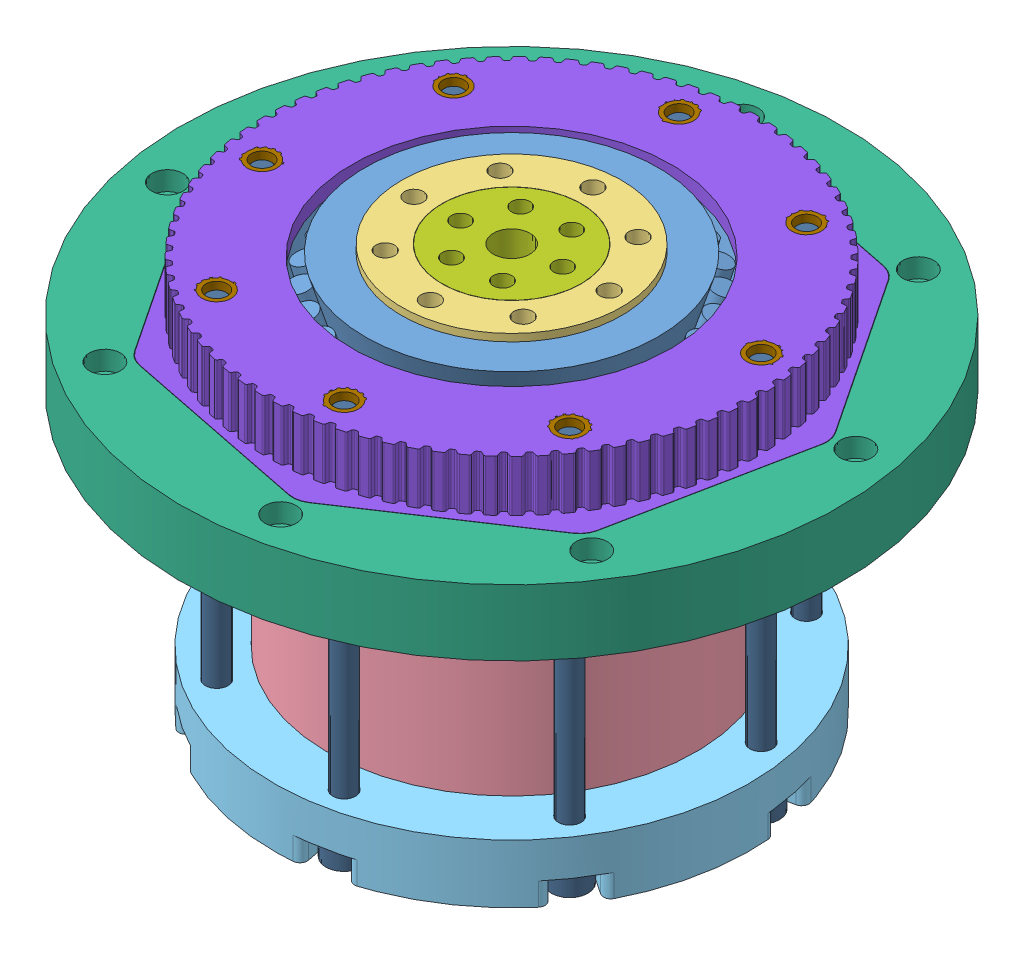
SolidWorks assembly Assemblage1, configuration Défaut. Lengths in mm.
Overall size (211.39 121 211.39).
25 component instances, 11 part files, 51 mates.
Components (placement in the parent):
- Roulement Conique 95x60x23-1: Roulement Conique 95x60x23 [Défaut] at (-13.8203 2.5153 0) x (-0.853201 0 0.521582) z (-0.521582 0 -0.853201) size (95 23 95)
- Roulement 68x40x15-1: Roulement 68x40x15 [Défaut] at (-13.8203 -87.4847 0) size (68 15 68)
- BaguePivot1-1: BaguePivot1 [Défaut] at (-13.8203 27.5153 0) x (-0.768543 0 -0.639798) z (-0.639798 0 0.768543) size (60 20 60)
- Tube d100x100-1: Tube d100x100 [Défaut] at (-13.8203 -73.4847 0) size (100.4 70 100.4)
- BagueInf1-1: BagueInf1 [Défaut] at (-13.8203 -87.4847 0) x (0.981157 0 -0.19321) z (0.19321 0 0.981157) size (130 20 130)
- BagueSup1-1: BagueSup1 [Défaut] at (-13.8203 -9.4847 0) x (0.981157 0 -0.19321) z (0.19321 0 0.981157) size (180 20 180)
- AxePivot1-1: AxePivot1 [Défaut] at (-13.8203 -82.4847 0) x (0.920291 0 0.391234) z (-0.391234 0 0.920291) size (41 110 41)
- BagueSup2-1: BagueSup2 [Défaut] at (-13.8203 8.5153 0) x (0.981157 0 -0.19321) z (0.19321 0 0.981157) size (148.13 16 148.13)
- M6_insert-2: M6_insert [Défaut] at (-2.6142 11.8153 56.9071) size (8.69 12.7 8.66)
- M6_insert-3: M6_insert [Défaut] at (-46.1358 11.8153 48.1634) size (8.69 12.7 8.66)
- M6_insert-4: M6_insert [Défaut] at (-70.7275 11.8153 11.2062) size (8.69 12.7 8.66)
- M6_insert-5: M6_insert [Défaut] at (-61.9837 11.8153 -32.3155) size (8.69 12.7 8.66)
- M6_insert-6: M6_insert [Défaut] at (34.343 11.8153 32.3155) size (8.69 12.7 8.66)
- M6_insert-7: M6_insert [Défaut] at (43.0868 11.8153 -11.2062) size (8.69 12.7 8.66)
- M6_insert-8: M6_insert [Défaut] at (18.4951 11.8153 -48.1634) size (8.69 12.7 8.66)
- M6_insert-9: M6_insert [Défaut] at (-25.0265 11.8153 -56.9071) size (8.69 12.7 8.66)
- M6x100_vis-2: M6x100_vis [Défaut] at (18.4951 -83.2847 -48.1634) x (1 0 0) z (0 1 0) size (10 10 106)
- M6x100_vis-3: M6x100_vis [Défaut] at (-25.0265 -83.2847 -56.9071) x (1 0 0) z (0 1 0) size (10 10 106)
- M6x100_vis-4: M6x100_vis [Défaut] at (-61.9837 -83.2847 -32.3155) x (1 0 0) z (0 1 0) size (10 10 106)
- M6x100_vis-5: M6x100_vis [Défaut] at (-70.7275 -83.2847 11.2062) x (1 0 0) z (0 1 0) size (10 10 106)
- M6x100_vis-6: M6x100_vis [Défaut] at (-46.1358 -83.2847 48.1634) x (1 0 0) z (0 1 0) size (10 10 106)
- M6x100_vis-7: M6x100_vis [Défaut] at (-2.6142 -83.2847 56.9071) x (1 0 0) z (0 1 0) size (10 10 106)
- M6x100_vis-8: M6x100_vis [Défaut] at (34.343 -83.2847 32.3155) x (1 0 0) z (0 1 0) size (10 10 106)
- M6x100_vis-9: M6x100_vis [Défaut] at (43.0868 -83.2847 -11.2062) x (1 0 0) z (0 1 0) size (10 10 106)
- BouchonInf1-1: BouchonInf1 [Défaut] at (-13.8203 -83.4847 0) x (-0.920291 0 -0.391234) z (-0.391234 0 0.920291) size (50 10 50)
Mates (geometry in assembly coordinates):
- Coaxiale1: concentric anti-aligned: cylinder of Roulement Conique 95x60x23-1 through (-13.8203 2.5153 0) axis (0 -1 0) radius 30; cylinder of BaguePivot1-1 through (-13.8203 7.5153 0) axis (0 1 0) radius 30
- Coaxiale2: concentric aligned: cylinder of Roulement 68x40x15-1 through (-13.8203 -72.4847 0) axis (0 -1 0) radius 34; cylinder of BagueInf1-1 through (-13.8203 -87.4847 0) axis (0 -1 0) radius 34.05
- Coïncidente1: coincident anti-aligned: plane of Roulement 68x40x15-1 through (-13.8203 -72.4847 0) normal (0 1 0); plane of BagueInf1-1 through (-47.2287 -72.4847 6.5788) normal (0 -1 0)
- Coaxiale3: concentric aligned: cylinder of Tube d100x100-1 through (-13.8203 -3.4847 0) axis (0 -1 0) radius 50.2; cylinder of BagueInf1-1 through (-13.8203 -87.4847 0) axis (0 -1 0) radius 50.3
- Coïncidente2: coincident anti-aligned: plane of Tube d100x100-1 through (-13.8203 -73.4847 0) normal (0 -1 0); plane of BagueInf1-1 through (-60.0328 -73.4847 9.1002) normal (0 1 0)
- Coaxiale4: concentric aligned: cylinder of Tube d100x100-1 through (-13.8203 -3.4847 0) axis (0 -1 0) radius 50.2; cylinder of BagueSup1-1 through (-13.8203 -9.4847 0) axis (0 -1 0) radius 50.3
- Coïncidente3: coincident anti-aligned: plane of Tube d100x100-1 through (-13.8203 -3.4847 0) normal (0 1 0); plane of BagueSup1-1 through (-63.1725 -3.4847 9.7185) normal (0 -1 0)
- Coaxiale5: concentric aligned: cylinder of Roulement Conique 95x60x23-1 through (-13.8203 2.5153 0) axis (0 -1 0) radius 47.5; cylinder of BagueSup1-1 through (-13.8203 -9.4847 0) axis (0 -1 0) radius 47.55
- Coïncidente4: coincident anti-aligned: plane of Roulement Conique 95x60x23-1 through (26.7067 2.5153 -24.7752) normal (0 -1 0); plane of BagueSup1-1 through (-53.6063 2.5153 7.8347) normal (0 1 0)
- Coaxiale6: concentric aligned: cylinder of BagueInf1-1 through (-25.0265 -67.4847 -56.9071) axis (0 -1 0) radius 3.1; cylinder of BagueSup1-1 through (-25.0265 10.5153 -56.9071) axis (0 -1 0) radius 3.1
- Coaxiale7: concentric aligned: cylinder of BaguePivot1-1 through (-13.8203 7.5153 0) axis (0 1 0) radius 19; cylinder of AxePivot1-1 through (-13.8203 5.5153 0) axis (0 1 0) radius 18.95
- Coaxiale8: concentric aligned: cylinder of Roulement Conique 95x60x23-1 through (-13.8203 2.5153 0) axis (0 -1 0) radius 47.5; cylinder of BagueSup2-1 through (-13.8203 24.5153 0) axis (0 -1 0) radius 47.55
- Coaxiale9: concentric anti-aligned: cylinder of BagueSup1-1 through (43.0868 10.5153 -11.2062) axis (0 -1 0) radius 3.1; cylinder of BagueSup2-1 through (43.0868 8.5153 -11.2062) axis (0 1 0) radius 3.1
- Coïncidente7: coincident anti-aligned: plane of BagueSup1-1 through (-13.8203 8.5153 0) normal (0 1 0); plane of BagueSup2-1 through (-13.8203 8.5153 0) normal (0 -1 0)
- Coaxiale101: concentric anti-aligned: cylinder of BagueSup2-1 through (-2.6142 11.7153 56.9071) axis (0 1 0) radius 4; cylinder of M6_insert-2 through (-2.6142 24.5153 56.9071) axis (0 -1 0) radius 2.9
- Coaxiale111: concentric anti-aligned: cylinder of BagueSup2-1 through (-46.1358 11.7153 48.1634) axis (0 1 0) radius 4; cylinder of M6_insert-3 through (-46.1358 24.5153 48.1634) axis (0 -1 0) radius 2.9
- Coaxiale121: concentric anti-aligned: cylinder of BagueSup2-1 through (-70.7275 11.7153 11.2062) axis (0 1 0) radius 4; cylinder of M6_insert-4 through (-70.7275 24.5153 11.2062) axis (0 -1 0) radius 2.9
- Coaxiale131: concentric anti-aligned: cylinder of BagueSup2-1 through (-61.9837 11.7153 -32.3155) axis (0 1 0) radius 4; cylinder of M6_insert-5 through (-61.9837 24.5153 -32.3155) axis (0 -1 0) radius 2.9
- Coaxiale141: concentric anti-aligned: cylinder of BagueSup2-1 through (34.343 11.7153 32.3155) axis (0 1 0) radius 4; cylinder of M6_insert-6 through (34.343 24.5153 32.3155) axis (0 -1 0) radius 2.9
- Coaxiale151: concentric anti-aligned: cylinder of BagueSup2-1 through (43.0868 11.7153 -11.2062) axis (0 1 0) radius 4; cylinder of M6_insert-7 through (43.0868 24.5153 -11.2062) axis (0 -1 0) radius 2.9
- Coaxiale161: concentric anti-aligned: cylinder of BagueSup2-1 through (18.4951 11.7153 -48.1634) axis (0 1 0) radius 4; cylinder of M6_insert-8 through (18.4951 24.5153 -48.1634) axis (0 -1 0) radius 2.9
- Coaxiale171: concentric anti-aligned: cylinder of BagueSup2-1 through (-25.0265 11.7153 -56.9071) axis (0 1 0) radius 4; cylinder of M6_insert-9 through (-25.0265 24.5153 -56.9071) axis (0 -1 0) radius 2.9
- Coïncidente8: coincident aligned: plane of BagueSup2-1 through (-13.8203 24.5153 0) normal (0 1 0); circle of M6_insert-2
- Coïncidente9: coincident aligned: plane of BagueSup2-1 through (-13.8203 24.5153 0) normal (0 1 0); circle of M6_insert-3
- Coïncidente10: coincident aligned: plane of BagueSup2-1 through (-13.8203 24.5153 0) normal (0 1 0); circle of M6_insert-4
- Coïncidente11: coincident aligned: plane of BagueSup2-1 through (-13.8203 24.5153 0) normal (0 1 0); circle of M6_insert-5
- Coïncidente12: coincident aligned: plane of BagueSup2-1 through (-13.8203 24.5153 0) normal (0 1 0); circle of M6_insert-9
- Coïncidente13: coincident aligned: plane of BagueSup2-1 through (-13.8203 24.5153 0) normal (0 1 0); circle of M6_insert-8
- Coïncidente14: coincident aligned: plane of BagueSup2-1 through (-13.8203 24.5153 0) normal (0 1 0); circle of M6_insert-7
- Coïncidente15: coincident aligned: plane of BagueSup2-1 through (-13.8203 24.5153 0) normal (0 1 0); circle of M6_insert-6
- Coaxiale181: concentric aligned: cylinder of M6x100_vis-2 through (18.4951 22.7153 -48.1634) axis (0 -1 0) radius 3; cylinder of BagueInf1-1 through (18.4951 -51.4039 -48.1634) axis (0 -1 0) radius 5.2
- Coaxiale191: concentric aligned: cylinder of M6x100_vis-3 through (-25.0265 22.7153 -56.9071) axis (0 -1 0) radius 3; cylinder of BagueInf1-1 through (-25.0265 -51.4039 -56.9071) axis (0 -1 0) radius 5.2
- Coaxiale201: concentric aligned: cylinder of M6x100_vis-4 through (-61.9837 22.7153 -32.3155) axis (0 -1 0) radius 3; cylinder of BagueInf1-1 through (-61.9837 -51.4039 -32.3155) axis (0 -1 0) radius 5.2
- Coaxiale211: concentric aligned: cylinder of M6x100_vis-5 through (-70.7275 22.7153 11.2062) axis (0 -1 0) radius 3; cylinder of BagueInf1-1 through (-70.7275 -51.4039 11.2062) axis (0 -1 0) radius 5.2
- Coaxiale221: concentric aligned: cylinder of M6x100_vis-6 through (-46.1358 22.7153 48.1634) axis (0 -1 0) radius 3; cylinder of BagueInf1-1 through (-46.1358 -51.4039 48.1634) axis (0 -1 0) radius 5.2
- Coaxiale231: concentric aligned: cylinder of M6x100_vis-7 through (-2.6142 22.7153 56.9071) axis (0 -1 0) radius 3; cylinder of BagueInf1-1 through (-2.6142 -51.4039 56.9071) axis (0 -1 0) radius 5.2
- Coaxiale241: concentric aligned: cylinder of M6x100_vis-8 through (34.343 22.7153 32.3155) axis (0 -1 0) radius 3; cylinder of BagueInf1-1 through (34.343 -51.4039 32.3155) axis (0 -1 0) radius 5.2
- Coaxiale251: concentric aligned: cylinder of M6x100_vis-9 through (43.0868 22.7153 -11.2062) axis (0 -1 0) radius 3; cylinder of BagueInf1-1 through (43.0868 -51.4039 -11.2062) axis (0 -1 0) radius 5.2
- Coïncidente16: coincident: plane of BagueInf1-1 through (18.4951 -77.2847 -48.1634) normal (0 -1 0); circle of M6x100_vis-2
- Coïncidente17: coincident: plane of BagueInf1-1 through (-25.0265 -77.2847 -56.9071) normal (0 -1 0); circle of M6x100_vis-3
- Coïncidente18: coincident: plane of BagueInf1-1 through (-25.0265 -77.2847 -56.9071) normal (0 -1 0); circle of M6x100_vis-4
- Coïncidente19: coincident: plane of BagueInf1-1 through (-25.0265 -77.2847 -56.9071) normal (0 -1 0); circle of M6x100_vis-8
- Coïncidente20: coincident: plane of BagueInf1-1 through (-25.0265 -77.2847 -56.9071) normal (0 -1 0); circle of M6x100_vis-9
- Coïncidente21: coincident: plane of BagueInf1-1 through (-25.0265 -77.2847 -56.9071) normal (0 -1 0); circle of M6x100_vis-7
- Coïncidente22: coincident: plane of BagueInf1-1 through (-25.0265 -77.2847 -56.9071) normal (0 -1 0); circle of M6x100_vis-6
- Coïncidente23: coincident: plane of BagueInf1-1 through (-25.0265 -77.2847 -56.9071) normal (0 -1 0); circle of M6x100_vis-5
- Coaxiale252: concentric anti-aligned: cylinder of Roulement 68x40x15-1 through (-13.8203 -72.4847 0) axis (0 -1 0) radius 20; cylinder of BouchonInf1-1 through (-13.8203 -87.4847 0) axis (0 1 0) radius 19.95
- Coïncidente24: coincident anti-aligned: plane of Roulement 68x40x15-1 through (-13.8203 -87.4847 0) normal (0 -1 0); plane of BouchonInf1-1 through (-13.8203 -87.4847 0) normal (0 1 0)
- Coaxiale253: concentric anti-aligned: cylinder of AxePivot1-1 through (-6.3031 -32.4847 9.9871) axis (0 -1 0) radius 2.5; cylinder of BouchonInf1-1 through (-6.3031 -87.4847 9.9871) axis (0 1 0) radius 2.5
- Coïncidente25: coincident aligned: plane of BaguePivot1-1 through (-13.8203 27.5153 0) normal (0 1 0); plane of AxePivot1-1 through (-13.8203 27.5153 0) normal (0 1 0)
- Distance1: distance = 2 mm aligned: plane of Roulement Conique 95x60x23-1 through (20.3077 25.5153 -20.8633) normal (0 1 0); plane of BaguePivot1-1 through (-13.8203 27.5153 0) normal (0 1 0)
